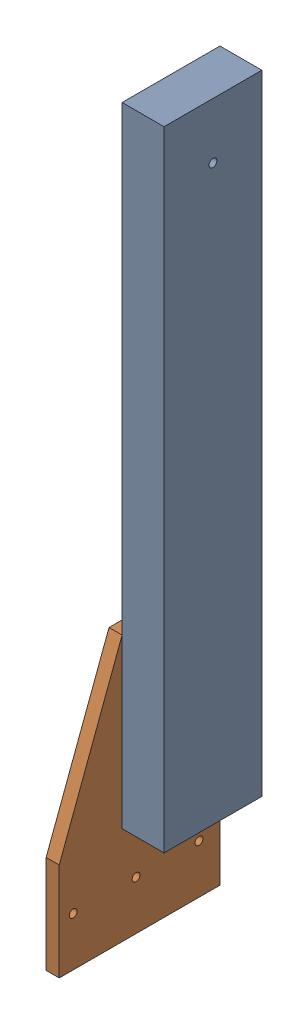
SolidWorks assembly TE-23033, configuration Default. Lengths in mm.
Overall size (50.01 660.4 146.05).
2 component instances, 2 part files, 3 mates.
Components (placement in the parent):
- TE-23011-1: TE-23011 [Default] at (191.803 660.4 12.0001) x (1 0 0) z (0 -1 0) size (38.1 88.9 571.5)
- TE-23012-1: TE-23012 [Default] at (172.753 0 -32.4499) x (-1 0 0) z (0 0 -1) size (11.91 241.3 146.05)
Mates (geometry in assembly coordinates):
- Coincident1: coincident aligned: plane of Cone Ramp Vertical-1 through (172.753 88.9 -32.4499) normal (0 0 -1); plane of Cone Ramp Gusset-1 through (160.8468 0 -32.4499) normal (0 0 -1)
- Distance1: distance = 88.9 mm aligned: plane of Cone Ramp Vertical-1 through (191.803 88.9 12.0001) normal (0 -1 0); plane of Cone Ramp Gusset-1 through (160.8468 0 113.6001) normal (0 -1 0)
- Coincident3: coincident anti-aligned: plane of Cone Ramp Vertical-1 through (172.753 88.9 -32.4499) normal (-1 0 0); plane of Cone Ramp Gusset-1 through (172.753 0 -32.4499) normal (1 0 0)
